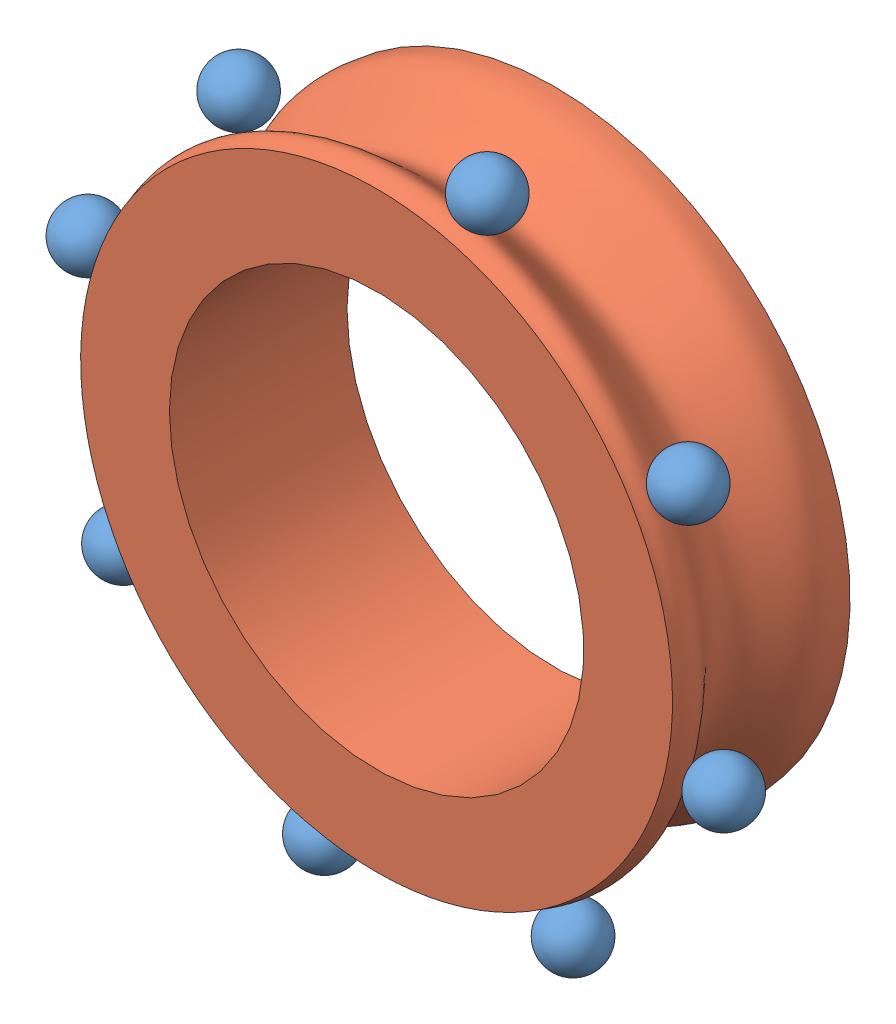
SolidWorks assembly Assem1, configuration Default. Lengths in mm.
Overall size (123.55 123.55 32.78).
9 component instances, 2 part files, 2 mates.
Components (placement in the parent):
- as2-1: as2 [Default] at (6.6692 -57.0815 53.0426) x (0.017288 0.60008 -0.799753) z (0.952228 -0.253799 -0.16985) size (10 10 10)
- as1-1: as1 [Default] at (20.4282 -3.3665 57.9879) size (106.91 106.91 30)
- as2-2: as2 [Default] at (-27.2831 -31.6197 53.0426) x (0.436545 0.412096 -0.799753) z (0.493864 -0.852789 -0.16985) size (10 10 10)
- as2-3: as2 [Default] at (-33.2869 10.3925 53.0426) x (0.60008 -0.017288 -0.799753) z (-0.253799 -0.952228 -0.16985) size (10 10 10)
- as2-4: as2 [Default] at (-7.8251 44.3448 53.0426) x (0.412096 -0.436545 -0.799753) z (-0.852789 -0.493864 -0.16985) size (10 10 10)
- as2-5: as2 [Default] at (34.1871 50.3485 53.0426) x (-0.017288 -0.60008 -0.799753) z (-0.952228 0.253799 -0.16985) size (10 10 10)
- as2-6: as2 [Default] at (68.1394 24.8867 53.0426) x (-0.436545 -0.412096 -0.799753) z (-0.493864 0.852789 -0.16985) size (10 10 10)
- as2-7: as2 [Default] at (74.1432 -17.1254 53.0426) x (-0.60008 0.017288 -0.799753) z (0.253799 0.952228 -0.16985) size (10 10 10)
- as2-8: as2 [Default] at (48.6814 -51.0778 53.0426) x (-0.412096 0.436545 -0.799753) z (0.852789 0.493864 -0.16985) size (10 10 10)
Mates (geometry in assembly coordinates):
- Tangent3: tangent anti-aligned: sphere of as2-1; face of as1-1
- Tangent4: tangent anti-aligned: edge_curve of as2-1
